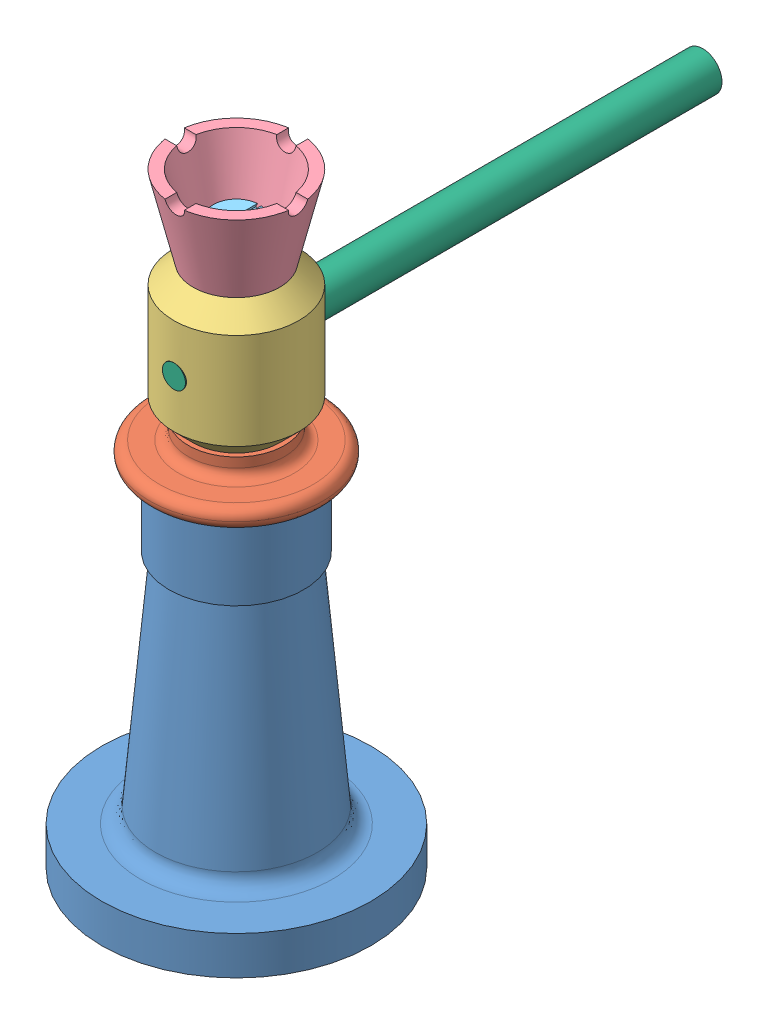
SolidWorks assembly Screw Jack Assembly, configuration Default. Lengths in mm.
Overall size (140 315.07 312.5).
7 component instances, 7 part files, 12 mates.
Components (placement in the parent):
- Jack Body-1: Jack Body [Default] at origin size (140 182.78 140)
- Nut-1: Nut [Default] at (0 74.6342 0) x (0.988694 0 -0.149946) z (0.149946 0 0.988694) size (90 45 90)
- Screw-3: Screw [Default] at (0 34.4079 0) size (65 240 65)
- Cup-2: Cup [Default] at (0 257.6175 0) size (64.81 42.29 64.81)
- washer-1: washer [Default] at (0 259.6248 0) (suppressed, hidden)
- Screw1-1: Screw1 [Default] at (0 225.2201 0) size (24 30 23.92)
- Tommy bar-1: Tommy bar [Default] at (0 147.5 -162.903) x (1 0 0) z (0 -1 0) size (20 275 20)
Mates (geometry in assembly coordinates):
- Concentric1: concentric aligned: cylinder of Jack Body-1 through (0 -90.2789 0) axis (0 -1 0) radius 25; cylinder of Nut-1 through (0 -5.9966 0) axis (0 -1 0) radius 19
- Coincident1: coincident anti-aligned: plane of Jack Body-1 through (25 92.5 0) normal (0 1 0); plane of Nut-1 through (44.4912 92.5 -6.7476) normal (0 -1 0)
- Concentric2: concentric aligned: cylinder of Nut-1 through (0 -5.9966 0) axis (0 -1 0) radius 19; cylinder of Screw-3 through (0 135.024 0) axis (0 -1 0) radius 19
- Coincident6: coincident anti-aligned: plane of Nut-1 through (18.7852 112.5 -2.849) normal (0 1 0); plane of Screw-3 through (19 112.5 0) normal (0 -1 0)
- Coincident7: coincident anti-aligned: plane of Screw-3 through (32.5 182.5 0) normal (0 1 0); plane of Cup-2 through (11.25 182.5 0) normal (0 -1 0)
- Concentric4: concentric anti-aligned: cylinder of Screw-3 through (0 135.024 0) axis (0 -1 0) radius 11; cone of Cup-2 through (0 194.5 0) axis (0 1 0)
- Coincident8: coincident anti-aligned: plane of Cup-2 through (11 194.5 0) normal (0 1 0); plane of Washer-1 through (7.25 194.5 0) normal (0 -1 0)
- Concentric5: concentric anti-aligned: cylinder of Screw-3 through (0 135.024 0) axis (0 -1 0) radius 11; cylinder of Washer-1 through (0 314.0678 0) axis (0 1 0) radius 7.25
- Coincident9: coincident aligned: plane of Washer-1 through (12.5 202.5 0) normal (0 1 0); plane of Screw1-1 through (0 202.5 0) normal (0 1 0)
- Concentric6: concentric aligned: cylinder of Washer-1 through (0 314.0678 0) axis (0 1 0) radius 7.25; cylinder of Screw1-1 through (0 278.9739 0) axis (0 1 0) radius 6
- Concentric7: concentric anti-aligned: cylinder of Screw-3 through (0 147.5 -55) axis (0 0 1) radius 6; cylinder of Tommy bar-1 through (0 147.5 -101.2239) axis (0 0 -1) radius 6
- Tangent5: tangent aligned: cylinder of Screw-3 through (0 135.024 0) axis (0 -1 0) radius 32.5; plane of Tommy bar-1 through (0 147.5 32.5) normal (0 0 1)
